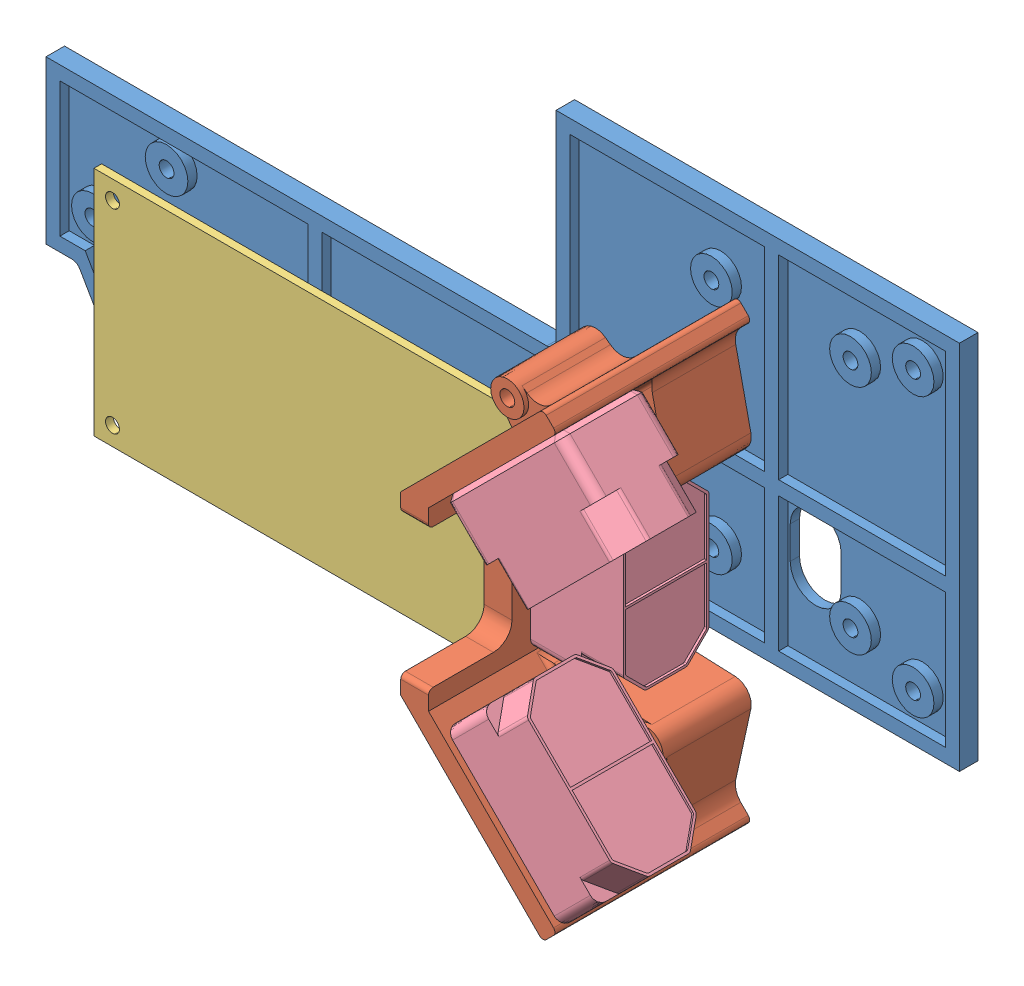
SolidWorks assembly Assemblage, configuration Défaut. Lengths in mm.
Overall size (197 112.26 71).
6 component instances, 4 part files, 12 mates.
Components (placement in the parent):
- ChassisInf-1: ChassisInf [Défaut] at (-6.4382 22.7336 -2) size (197 103 4)
- ChassisSup-1: ChassisSup [Défaut] at (53.5618 22.7336 27) x (0 1 0) z (0 0 1) size (98.52 37.2 42)
- STM32-1: STM32 [Défaut] at (-32.9382 -11.2664 12) size (100 50 1.66)
- TFMiniPlus-1: TFMiniPlus [Défaut] at (65.5618 22.7336 38.75) x (0 -1 0) z (-1 0 0) size (35 24.5 21)
- TFMiniPlus-2: TFMiniPlus [Défaut] at (74.3557 41.829 59.25) x (-0.707107 -0.707107 0) z (-0.707107 0.707107 0) size (35 24.5 21)
- TFMiniPlus-3: TFMiniPlus [Défaut] at (74.3557 3.6383 59.25) x (0.707107 -0.707107 0) z (-0.707107 -0.707107 0) size (35 24.5 21)
Mates (geometry in assembly coordinates):
- Coaxiale1: concentric aligned: cylinder of ChassisInf-1 through (38.5618 47.7336 0) axis (0 0 -1) radius 1.6; cylinder of ChassisSup-1 through (38.5618 47.7336 29) axis (0 0 -1) radius 1.6
- Coaxiale2: concentric aligned: cylinder of ChassisInf-1 through (68.5618 -2.2664 0) axis (0 0 -1) radius 1.6; cylinder of ChassisSup-1 through (68.5618 -2.2664 29) axis (0 0 -1) radius 1.6
- Distance1: distance = 25 mm anti-aligned: plane of ChassisInf-1 through (68.5618 47.7336 2) normal (0 0 1); plane of ChassisSup-1 through (53.5618 22.7336 27) normal (0 0 -1)
- Coaxiale3: concentric aligned: cylinder of ChassisInf-1 through (13.0618 -32.2664 0) axis (0 0 -1) radius 1.6; cylinder of STM32-1 through (13.0618 -32.2664 13.66) axis (0 0 -1) radius 1.5
- Coaxiale6: concentric aligned: cylinder of ChassisInf-1 through (-78.9382 9.7336 0) axis (0 0 -1) radius 1.6; cylinder of STM32-1 through (-78.9382 9.7336 13.66) axis (0 0 -1) radius 1.5
- Distance2: distance = 10 mm anti-aligned: plane of ChassisInf-1 through (-78.9382 9.7336 2) normal (0 0 1); plane of STM32-1 through (-32.9382 -11.2664 12) normal (0 0 -1)
- Coïncidente4: coincident anti-aligned: plane of ChassisSup-1 through (44.5618 3.7336 49) normal (1 0 0); plane of TFMiniPlus-1 through (44.5618 22.7336 38.75) normal (-1 0 0)
- Coïncidente5: coincident anti-aligned: plane of ChassisSup-1 through (54.5618 51.7336 49) normal (0.707107 -0.707107 0); plane of TFMiniPlus-2 through (59.5064 56.6783 59.25) normal (-0.707107 0.707107 0)
- Coïncidente6: coincident anti-aligned: plane of ChassisSup-1 through (54.5618 -6.2664 49) normal (0.707107 0.707107 0); plane of TFMiniPlus-3 through (59.5064 -11.211 59.25) normal (-0.707107 -0.707107 0)
- Coaxiale7: concentric anti-aligned: circle of ChassisSup-1; circle of TFMiniPlus-2
- Coaxiale8: concentric anti-aligned: circle of ChassisSup-1; circle of TFMiniPlus-1
- Coaxiale9: concentric anti-aligned: circle of ChassisSup-1; circle of TFMiniPlus-3
